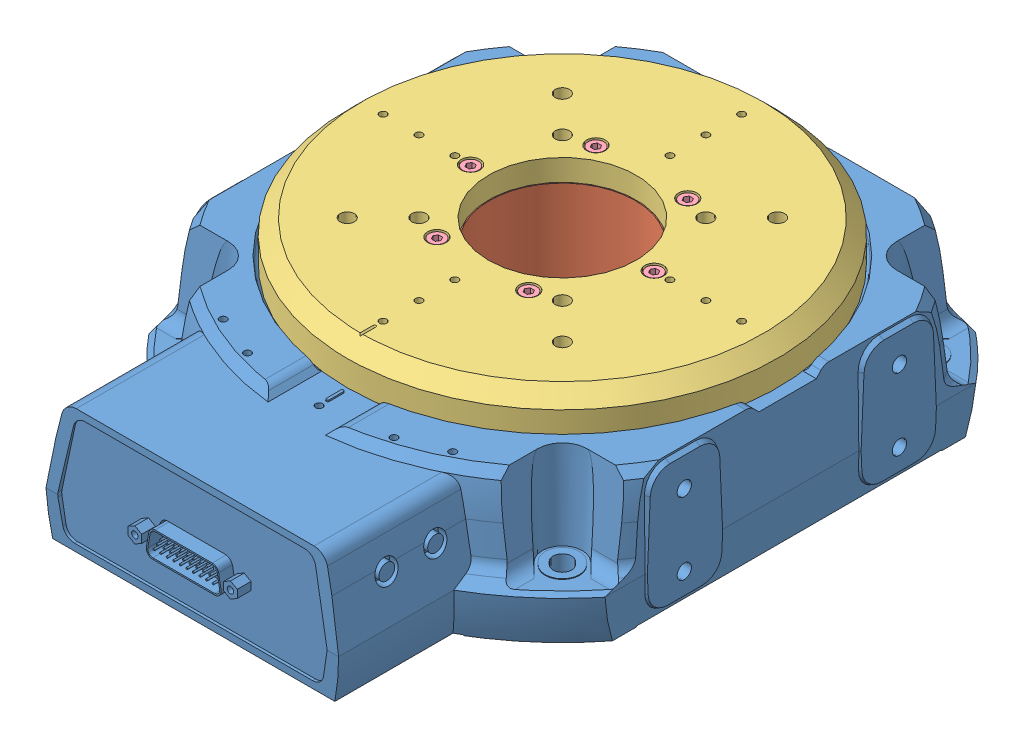
SolidWorks assembly RDQ, configuration RDQ150-AE57T10A-AP270. Lengths in mm.
Overall size (160 57.5 213.86).
9 component instances, 4 part files, 24 mates.
Components (placement in the parent):
- RDQ_base^RDQ-1: RDQ_base^RDQ [RDQ] at origin (virtual)
- RDQ_spindle^RDQ-1: RDQ_spindle^RDQ [Default] at origin (virtual)
- AP270^RDQ-1: AP270^RDQ [Default] at (0 57.5 0) (virtual)
- Screw_SHCS^RDQ-1: Screw_SHCS^RDQ [M3 x 08mm] at (-16 54.2 27.7128) (virtual)
- Screw_SHCS^RDQ-2: Screw_SHCS^RDQ [M3 x 08mm] at (-32 54.2 0) (virtual)
- Screw_SHCS^RDQ-3: Screw_SHCS^RDQ [M3 x 08mm] at (-16 54.2 -27.7128) (virtual)
- Screw_SHCS^RDQ-4: Screw_SHCS^RDQ [M3 x 08mm] at (16 54.2 -27.7128) (virtual)
- Screw_SHCS^RDQ-5: Screw_SHCS^RDQ [M3 x 08mm] at (32 54.2 0) (virtual)
- Screw_SHCS^RDQ-6: Screw_SHCS^RDQ [M3 x 08mm] at (16 54.2 27.7128) (virtual)
Mates (geometry in assembly coordinates):
- Home Position: coincident aligned: plane of Copy of RDQ_spindle^RDQ-1 through (0 0 0) normal (0 0 1); plane of assembly through (0 0 0) normal (0 0 1)
- Coincident2: coincident: point of Copy of RDQ_spindle^RDQ-1
- Coincident3: coincident aligned: plane of Copy of RDQ_spindle^RDQ-1 through (0 0 0) normal (0 1 0); plane of assembly through (0 0 0) normal (0 1 0)
- Coincident4: coincident anti-aligned: plane of Copy of RDQ_spindle^RDQ-1 through (35 50 0) normal (0 1 0); plane of AP270-1 through (25.75 50 0) normal (0 -1 0)
- Concentric1: concentric: cylinder of Copy of AP270^RDQ-1 through (0 57.5 0) axis (0 1 0) radius 25.75
- Coincident7: coincident aligned: plane of Copy of RDQ_spindle^RDQ-1 through (0 0 0) normal (1 0 0); plane of AP270-1 through (0 57.5 0) normal (1 0 0)
- Concentric21: concentric anti-aligned: cylinder of Copy of AP270^RDQ-1 through (-16 57.5 27.7128) axis (0 1 0) radius 1.7; cylinder of Screw_SHCS-1 through (-16 46.2 27.7128) axis (0 -1 0) radius 1.5
- Coincident81: coincident anti-aligned: plane of Copy of AP270^RDQ-1 through (-14.3 54.2 27.7128) normal (0 1 0); plane of Screw_SHCS-1 through (-14.5 54.2 27.7128) normal (0 -1 0)
- Concentric31: concentric anti-aligned: cylinder of Copy of AP270^RDQ-1 through (-32 57.5 0) axis (0 1 0) radius 1.7; cylinder of Screw_SHCS-2 through (-32 46.2 0) axis (0 -1 0) radius 1.5
- Coincident91: coincident anti-aligned: plane of Copy of AP270^RDQ-1 through (-30.3 54.2 0) normal (0 1 0); plane of Screw_SHCS-2 through (-30.5 54.2 0) normal (0 -1 0)
- Concentric41: concentric anti-aligned: cylinder of Copy of AP270^RDQ-1 through (-16 57.5 -27.7128) axis (0 1 0) radius 1.7; cylinder of Screw_SHCS-3 through (-16 46.2 -27.7128) axis (0 -1 0) radius 1.5
- Coincident101: coincident anti-aligned: plane of Copy of AP270^RDQ-1 through (-14.3 54.2 -27.7128) normal (0 1 0); plane of Screw_SHCS-3 through (-14.5 54.2 -27.7128) normal (0 -1 0)
- Concentric51: concentric anti-aligned: cylinder of Copy of AP270^RDQ-1 through (16 57.5 -27.7128) axis (0 1 0) radius 3.25; cylinder of Screw_SHCS-4 through (16 46.2 -27.7128) axis (0 -1 0) radius 1.5
- Coincident111: coincident anti-aligned: plane of Copy of AP270^RDQ-1 through (17.7 54.2 -27.7128) normal (0 1 0); plane of Screw_SHCS-4 through (17.5 54.2 -27.7128) normal (0 -1 0)
- Concentric61: concentric anti-aligned: cylinder of Copy of AP270^RDQ-1 through (32 57.5 0) axis (0 1 0) radius 1.7; cylinder of Screw_SHCS-5 through (32 46.2 0) axis (0 -1 0) radius 1.5
- Coincident121: coincident anti-aligned: plane of Copy of AP270^RDQ-1 through (33.7 54.2 0) normal (0 1 0); plane of Screw_SHCS-5 through (33.5 54.2 0) normal (0 -1 0)
- Concentric71: concentric anti-aligned: cylinder of Copy of AP270^RDQ-1 through (16 57.5 27.7128) axis (0 1 0) radius 1.7; cylinder of Screw_SHCS-6 through (16 46.2 27.7128) axis (0 -1 0) radius 1.5
- Coincident131: coincident anti-aligned: plane of Copy of AP270^RDQ-1 through (17.7 54.2 27.7128) normal (0 1 0); plane of Screw_SHCS-6 through (17.5 54.2 27.7128) normal (0 -1 0)
- Parallel1: parallel aligned: plane of Copy of AP270^RDQ-1 through (0 57.5 0) normal (0 0 1); plane of Screw_SHCS-1 through (-16 54.2 27.7128) normal (0 0 1)
- Parallel2: parallel aligned: plane of Copy of AP270^RDQ-1 through (0 57.5 0) normal (0 0 1); plane of Screw_SHCS-2 through (-32 54.2 0) normal (0 0 1)
- Parallel3: parallel aligned: plane of Copy of AP270^RDQ-1 through (0 57.5 0) normal (0 0 1); plane of Screw_SHCS-3 through (-16 54.2 -27.7128) normal (0 0 1)
- Parallel4: parallel aligned: plane of Copy of AP270^RDQ-1 through (0 57.5 0) normal (0 0 1); plane of Screw_SHCS-4 through (16 54.2 -27.7128) normal (0 0 1)
- Parallel5: parallel aligned: plane of Copy of AP270^RDQ-1 through (0 57.5 0) normal (0 0 1); plane of Screw_SHCS-5 through (32 54.2 0) normal (0 0 1)
- Parallel6: parallel aligned: plane of Copy of AP270^RDQ-1 through (0 57.5 0) normal (0 0 1); plane of Screw_SHCS-6 through (16 54.2 27.7128) normal (0 0 1)
